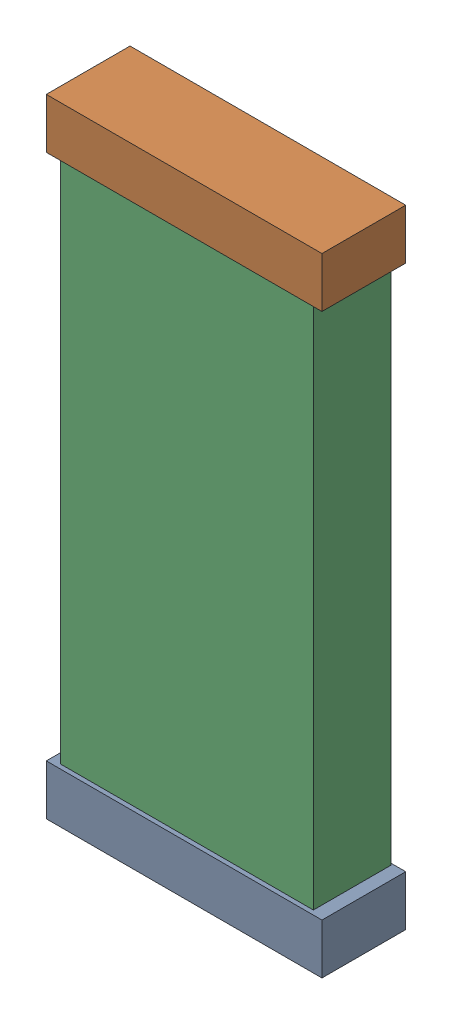
SolidWorks assembly PWR1, configuration Default. Lengths in mm.
Overall size (1.51 3.44 0.46).
6 component instances, 2 part files, 0 mates.
Components (placement in the parent):
- 744575856_2-1: 744575856_2 [Default] at (47.1501 59.1191 -0.8715) size (1.51 0.28 0.46)
  - Extruded (27)-1: Extruded (27) [Default] at origin size (1.51 0.28 0.46)
- 744575856_3-1: 744575856_3 [Default] at (47.15 62.2816 -0.8715) size (1.51 0.28 0.46)
  - Extruded (27)-1: Extruded (27) [Default] at origin size (1.51 0.28 0.46)
- 710423568_1-1: 710423568_1 [Default] at (47.1421 60.6941 -0.8615) size (1.38 3.05 0.42)
  - Extruded (28)-1: Extruded (28) [Default] at origin size (1.38 3.05 0.42)
